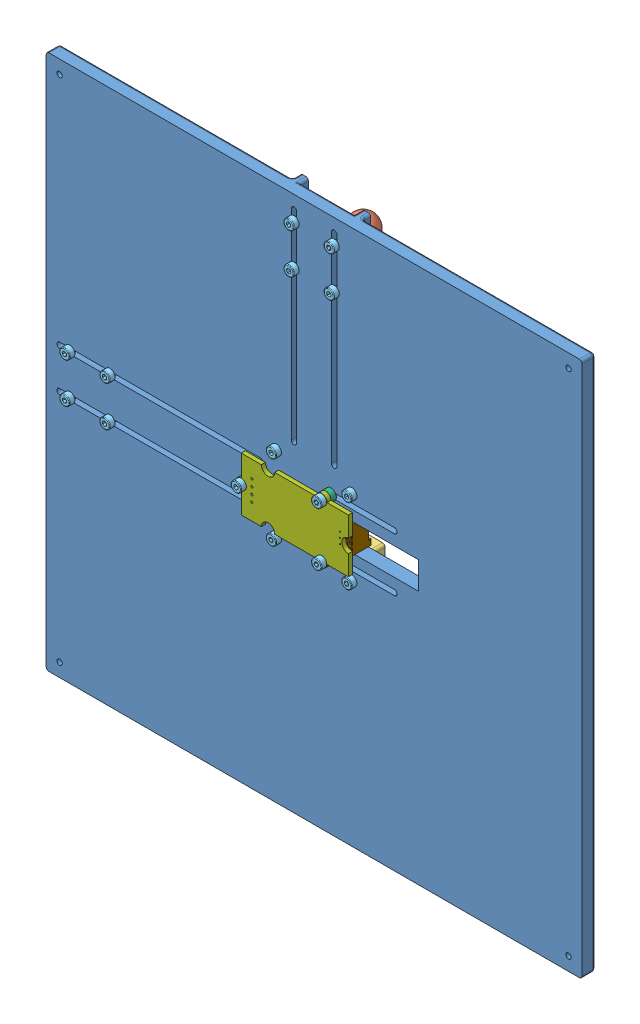
SolidWorks assembly plateau-complet, configuration Défaut. Lengths in mm.
Overall size (200 200 29.5).
45 component instances, 9 part files, 99 mates.
Components (placement in the parent):
- plateau-1: plateau [Défaut] at (22.8083 8.2939 197.5) size (200 200 8)
- support-sphere-ecrou_m2-4: support-sphere-ecrou_m2 [Défaut] at (-60.8917 8.2939 184.1699) x (0 -1 0) z (1 0 0) size (20 18.33 20)
- support-sphere-ecrou_m2-3: support-sphere-ecrou_m2 [Défaut] at (22.8083 91.9939 184.1699) x (1 0 0) z (0 1 0) size (20 18.33 20)
- support-fourchette-ecrou_m2-large-1: support-fourchette-ecrou_m2-large [Défaut] at (22.8083 8.2939 183.5) x (1 0 0) z (0 1 0) size (35 19 35)
- ecrou-h-6: ecrou-h [6007 HU M2] at (30.3083 99.4939 195.1) x (0.866025 -0.5 0) z (-0.5 -0.866025 0) size (4 1.6 4.62)
- ecrou-h-7: ecrou-h [6007 HU M2] at (15.3083 84.4939 195.1) x (-0.866025 -0.5 0) z (-0.5 0.866025 0) size (4 1.6 4.62)
- ecrou-h-8: ecrou-h [6007 HU M2] at (30.3083 84.4939 195.1) x (0.866025 0.5 0) z (0.5 -0.866025 0) size (4 1.6 4.62)
- ecrou-h-9: ecrou-h [6007 HU M2] at (15.3083 99.4939 195.1) x (0 -1 0) z (-1 0 0) size (4 1.6 4.62)
- ecrou-h-10: ecrou-h [6007 HU M2] at (-68.3917 15.7939 195.1) x (-0.5 -0.866025 0) z (-0.866025 0.5 0) size (4 1.6 4.62)
- ecrou-h-11: ecrou-h [6007 HU M2] at (-68.3917 0.7939 195.1) x (0.5 0.866025 0) z (0.866025 -0.5 0) size (4 1.6 4.62)
- ecrou-h-12: ecrou-h [6007 HU M2] at (-53.3917 0.7939 195.1) x (0.5 -0.866025 0) z (-0.866025 -0.5 0) size (4 1.6 4.62)
- ecrou-h-13: ecrou-h [6007 HU M2] at (-53.3917 15.7939 195.1) x (-0.5 -0.866025 0) z (-0.866025 0.5 0) size (4 1.6 4.62)
- vis-chc-15: vis-chc [Vis CHC M2x12] at (-53.3917 0.7939 202.5) x (0.832658 0.553787 0) z (0.553787 -0.832658 0) size (3.8 14 3.8)
- vis-chc-16: vis-chc [Vis CHC M2x12] at (-53.3917 15.7939 202.5) x (0.872712 0.488236 0) z (0.488236 -0.872712 0) size (3.8 14 3.8)
- vis-chc-17: vis-chc [Vis CHC M2x12] at (-68.3917 0.7939 202.5) x (0.878735 -0.477309 0) z (-0.477309 -0.878735 0) size (3.8 14 3.8)
- vis-chc-18: vis-chc [Vis CHC M2x12] at (-68.3917 15.7939 202.5) x (-0.020688 -0.999786 0) z (-0.999786 0.020688 0) size (3.8 14 3.8)
- vis-chc-19: vis-chc [Vis CHC M2x12] at (15.3083 84.4939 202.5) x (-0.459945 -0.887947 0) z (-0.887947 0.459945 0) size (3.8 14 3.8)
- vis-chc-20: vis-chc [Vis CHC M2x12] at (30.3083 84.4939 202.5) x (-0.307246 0.95163 0) z (0.95163 0.307246 0) size (3.8 14 3.8)
- vis-chc-21: vis-chc [Vis CHC M2x12] at (15.3083 99.4939 202.5) x (0.103271 -0.994653 0) z (-0.994653 -0.103271 0) size (3.8 14 3.8)
- vis-chc-22: vis-chc [Vis CHC M2x12] at (30.3083 99.4939 202.5) x (0.948564 0.316586 0) z (0.316586 -0.948564 0) size (3.8 14 3.8)
- vis-chc-23: vis-chc [Vis CHC M2x12] at (8.7083 22.3939 202.5) x (0.719096 0.694911 0) z (0.694911 -0.719096 0) size (3.8 14 3.8)
- vis-chc-24: vis-chc [Vis CHC M2x12] at (36.9083 22.3939 202.5) x (0.587191 0.809448 0) z (0.809448 -0.587191 0) size (3.8 14 3.8)
- vis-chc-25: vis-chc [Vis CHC M2x12] at (8.7083 -5.8061 202.5) x (0.239044 0.971009 0) z (0.971009 -0.239044 0) size (3.8 14 3.8)
- vis-chc-26: vis-chc [Vis CHC M2x12] at (36.9083 -5.8061 202.5) x (0.971464 0.237189 0) z (0.237189 -0.971464 0) size (3.8 14 3.8)
- ecrou-h-14: ecrou-h [6007 HU M2] at (8.7083 22.3939 195.16) x (0.866025 -0.5 0) z (-0.5 -0.866025 0) size (4 1.6 4.62)
- ecrou-h-15: ecrou-h [6007 HU M2] at (8.7083 -5.8061 195.16) x (0 -1 0) z (-1 0 0) size (4 1.6 4.62)
- ecrou-h-16: ecrou-h [6007 HU M2] at (36.9083 -5.8061 195.16) x (0.866025 -0.5 0) z (-0.5 -0.866025 0) size (4 1.6 4.62)
- ecrou-h-17: ecrou-h [6007 HU M2] at (36.9083 22.3939 195.16) x (0.866025 -0.5 0) z (-0.5 -0.866025 0) size (4 1.6 4.62)
- ecrou-h-18: ecrou-h [6007 HU M2] at (-72.1917 103.2939 200.5) x (0.866025 0.5 0) z (0.5 -0.866025 0) size (4 1.6 4.62)
- ecrou-h-19: ecrou-h [6007 HU M2] at (117.8083 103.2939 198.9) x (0.866025 0.5 0) z (-0.5 0.866025 0) size (4 1.6 4.62)
- ecrou-h-20: ecrou-h [6007 HU M2] at (-72.1917 -86.7061 200.5) x (0 -1 0) z (-1 0 0) size (4 1.6 4.62)
- ecrou-h-21: ecrou-h [6007 HU M2] at (117.8083 -86.7061 200.5) x (0 1 0) z (1 0 0) size (4 1.6 4.62)
- vis-chc-30: vis-chc [Vis CHC M2x8] at (29.1222 18.2939 206) x (-0.221467 -0.975168 0) z (-0.975168 0.221467 0) size (3.8 10 3.8)
- vis-chc-32: vis-chc [Vis CHC M2x8] at (29.1222 -1.7061 206) x (-0.923728 -0.383049 0) z (-0.383049 0.923728 0) size (3.8 10 3.8)
- vis-chc-33: vis-chc [Vis CHC M2x8] at (-0.8778 8.2939 206) x (-0.787107 -0.616816 0) z (-0.616816 0.787107 0) size (3.8 10 3.8)
- ecrou-h-24: ecrou-h [6007 HU M2] at (-0.8778 8.2939 197.9) x (0 -1 0) z (1 0 0) size (4 1.6 4.62)
- ecrou-h-25: ecrou-h [6007 HU M2] at (29.1222 -1.7061 197.9) x (0.866025 0.5 0) z (-0.5 0.866025 0) size (4 1.6 4.62)
- ecrou-h-26: ecrou-h [6007 HU M2] at (29.1222 18.2939 197.9) x (-0.866025 0.5 0) z (-0.5 -0.866025 0) size (4 1.6 4.62)
- entretoise-grove-1: entretoise-grove [Défaut] at (29.1222 18.2939 202.5) x (0.992185 0.124776 0) z (0 0 1) size (4 4 2)
- entretoise-grove-2: entretoise-grove [Défaut] at (-0.8778 8.2939 202.5) x (0.16979 0.98548 0) z (0 0 1) size (4 4 2)
- entretoise-grove-3: entretoise-grove [Défaut] at (29.1222 -1.7061 202.5) x (0.064788 0.997899 0) z (0 0 1) size (4 4 2)
- Grove IMU - droit-1: Grove IMU - droit [Défaut] at (21.1434 5.8987 163.25) x (0 -1 0) z (0 0 1) size (24 42 9.5)
  - Grove IMU Board-1: Grove IMU Board [Défaut] at (-2.3952 -22.0212 41.25) size (24 42 1.5)
  - MPU9150-1: MPU9150 [Défaut] at (-3.0078 -7.8003 40.45) size (4 4 0.8)
  - Connecteur Grove - droit-1: Connecteur Grove - droit [Défaut] at (-2.3952 11.9788 41.25) x (-1 0 0) z (0 -1 0) size (10 11 5)
Mates (geometry in assembly coordinates):
- Coïncidente5: coincident anti-aligned: plane of plateau-1 through (22.8083 8.2939 197.5) normal (0 0 -1); plane of support-sphere-ecrou_m2-4 through (-60.8917 8.2939 197.5) normal (0 0 1)
- Coïncidente8: coincident anti-aligned: plane of plateau-1 through (22.8083 8.2939 197.5) normal (0 0 -1); plane of support-sphere-ecrou_m2-3 through (22.8083 91.9939 197.5) normal (0 0 1)
- Coïncidente12: coincident anti-aligned: plane of plateau-1 through (22.8083 8.2939 197.5) normal (0 0 -1); plane of support-fourchette-ecrou_m2-large-1 through (22.8083 8.2939 197.5) normal (0 0 1)
- Coaxiale9: concentric anti-aligned: cylinder of support-sphere-ecrou_m2-3 through (30.3083 99.4939 197.501) axis (0 0 -1) radius 1; cylinder of ecrou-h-m2-6 through (30.3083 99.4939 193.5) axis (0 0 1) radius 0.7835
- Coïncidente26: coincident anti-aligned: plane of support-sphere-ecrou_m2-3 through (22.8083 91.9939 195.1) normal (0 0 -1); plane of ecrou-h-m2-6 through (32.6177 99.4939 195.1) normal (0 0 1)
- Parallèle1: parallel anti-aligned: plane of support-sphere-ecrou_m2-3 through (27.9783 99.4939 195.1) normal (0.866025 -0.5 0); plane of ecrou-h-m2-6 through (29.1536 101.4939 193.5) normal (-0.866025 0.5 0)
- Coaxiale10: concentric anti-aligned: cylinder of support-sphere-ecrou_m2-3 through (15.3083 99.4939 197.501) axis (0 0 -1) radius 1; cylinder of ecrou-h-m2-9 through (15.3083 99.4939 193.5) axis (0 0 1) radius 0.7835
- Parallèle2: parallel anti-aligned: plane of support-sphere-ecrou_m2-3 through (14.1433 101.5118 195.1) normal (0 -1 0); plane of ecrou-h-m2-9 through (16.463 101.4939 193.5) normal (0 1 0)
- Coïncidente29: coincident anti-aligned: plane of support-sphere-ecrou_m2-3 through (22.8083 91.9939 195.1) normal (0 0 -1); plane of ecrou-h-m2-9 through (16.463 97.4939 195.1) normal (0 0 1)
- Coaxiale11: concentric anti-aligned: cylinder of support-sphere-ecrou_m2-3 through (15.3083 84.4939 197.501) axis (0 0 -1) radius 1; cylinder of ecrou-h-m2-7 through (15.3083 84.4939 193.5) axis (0 0 1) radius 0.7835
- Parallèle3: parallel anti-aligned: plane of support-sphere-ecrou_m2-3 through (12.9783 84.4939 195.1) normal (0.866025 -0.5 0); plane of ecrou-h-m2-7 through (14.1536 86.4939 193.5) normal (-0.866025 0.5 0)
- Coïncidente31: coincident anti-aligned: plane of support-sphere-ecrou_m2-3 through (22.8083 91.9939 195.1) normal (0 0 -1); plane of ecrou-h-m2-7 through (14.1536 82.4939 195.1) normal (0 0 1)
- Coaxiale12: concentric anti-aligned: cylinder of support-sphere-ecrou_m2-3 through (30.3083 84.4939 197.501) axis (0 0 -1) radius 1; cylinder of ecrou-h-m2-8 through (30.3083 84.4939 193.5) axis (0 0 1) radius 0.7835
- Parallèle4: parallel anti-aligned: plane of support-sphere-ecrou_m2-3 through (32.6383 84.4939 195.1) normal (-0.866025 0.5 0); plane of ecrou-h-m2-8 through (31.463 82.4939 193.5) normal (0.866025 -0.5 0)
- Coïncidente32: coincident anti-aligned: plane of support-sphere-ecrou_m2-3 through (22.8083 91.9939 195.1) normal (0 0 -1); plane of ecrou-h-m2-8 through (31.463 86.4939 195.1) normal (0 0 1)
- Coaxiale13: concentric anti-aligned: cylinder of support-sphere-ecrou_m2-4 through (-68.3917 15.7939 197.501) axis (0 0 -1) radius 1; cylinder of ecrou-h-m2-10 through (-68.3917 15.7939 193.5) axis (0 0 1) radius 0.7835
- Coaxiale14: concentric anti-aligned: cylinder of support-sphere-ecrou_m2-4 through (-68.3917 0.7939 197.501) axis (0 0 -1) radius 1; cylinder of ecrou-h-m2-11 through (-68.3917 0.7939 193.5) axis (0 0 1) radius 0.7835
- Coaxiale15: concentric anti-aligned: cylinder of support-sphere-ecrou_m2-4 through (-53.3917 0.7939 197.501) axis (0 0 -1) radius 1; cylinder of ecrou-h-m2-12 through (-53.3917 0.7939 193.5) axis (0 0 1) radius 0.7835
- Coaxiale16: concentric anti-aligned: cylinder of support-sphere-ecrou_m2-4 through (-53.3917 15.7939 197.501) axis (0 0 -1) radius 1; cylinder of ecrou-h-m2-13 through (-53.3917 15.7939 193.5) axis (0 0 1) radius 0.7835
- Parallèle5: parallel anti-aligned: plane of support-sphere-ecrou_m2-4 through (-51.3738 16.9589 195.1) normal (-1 0 0); plane of ecrou-h-m2-13 through (-51.3917 14.6392 193.5) normal (1 0 0)
- Parallèle6: parallel anti-aligned: plane of support-sphere-ecrou_m2-4 through (-66.3738 16.9589 195.1) normal (-1 0 0); plane of ecrou-h-m2-10 through (-66.3917 14.6392 193.5) normal (1 0 0)
- Parallèle7: parallel anti-aligned: plane of support-sphere-ecrou_m2-4 through (-66.3738 -0.3711 195.1) normal (-0.5 0.866025 0); plane of ecrou-h-m2-11 through (-68.3917 -1.5155 193.5) normal (0.5 -0.866025 0)
- Parallèle8: parallel anti-aligned: plane of support-sphere-ecrou_m2-4 through (-51.3738 -0.3711 195.1) normal (-0.5 0.866025 0); plane of ecrou-h-m2-12 through (-53.3917 -1.5155 193.5) normal (0.5 -0.866025 0)
- Coïncidente37: coincident anti-aligned: plane of support-sphere-ecrou_m2-4 through (-60.8917 8.2939 195.1) normal (0 0 -1); plane of ecrou-h-m2-10 through (-68.3917 13.4845 195.1) normal (0 0 1)
- Coïncidente38: coincident anti-aligned: plane of support-sphere-ecrou_m2-4 through (-60.8917 8.2939 195.1) normal (0 0 -1); plane of ecrou-h-m2-13 through (-53.3917 13.4845 195.1) normal (0 0 1)
- Coïncidente39: coincident anti-aligned: plane of support-sphere-ecrou_m2-4 through (-60.8917 8.2939 195.1) normal (0 0 -1); plane of ecrou-h-m2-11 through (-68.3917 3.1033 195.1) normal (0 0 1)
- Coïncidente40: coincident anti-aligned: plane of support-sphere-ecrou_m2-4 through (-60.8917 8.2939 195.1) normal (0 0 -1); plane of ecrou-h-m2-12 through (-51.3917 -0.3608 195.1) normal (0 0 1)
- Coaxiale17: concentric anti-aligned: cylinder of support-sphere-ecrou_m2-3 through (30.3083 99.4939 197.501) axis (0 0 -1) radius 1; cylinder of vis-chc-m2x10-8 through (30.3083 99.4939 190.5) axis (0 0 1) radius 1
- Coaxiale18: concentric anti-aligned: cylinder of support-sphere-ecrou_m2-3 through (15.3083 99.4939 197.501) axis (0 0 -1) radius 1; cylinder of vis-chc-m2x10-9 through (15.3083 99.4939 190.5) axis (0 0 1) radius 1
- Coaxiale19: concentric anti-aligned: cylinder of support-sphere-ecrou_m2-3 through (30.3083 84.4939 197.501) axis (0 0 -1) radius 1; cylinder of vis-chc-m2x10-11 through (30.3083 84.4939 190.5) axis (0 0 1) radius 1
- Coaxiale20: concentric anti-aligned: cylinder of support-sphere-ecrou_m2-3 through (15.3083 84.4939 197.501) axis (0 0 -1) radius 1; cylinder of vis-chc-m2x10-10 through (15.3083 84.4939 190.5) axis (0 0 1) radius 1
- Coaxiale21: concentric anti-aligned: cylinder of support-sphere-ecrou_m2-4 through (-53.3917 0.7939 197.501) axis (0 0 -1) radius 1; cylinder of vis-chc-m2-15 through (-53.3917 0.7939 190.5) axis (0 0 1) radius 1
- Coaxiale22: concentric anti-aligned: cylinder of support-sphere-ecrou_m2-4 through (-68.3917 0.7939 197.501) axis (0 0 -1) radius 1; cylinder of vis-chc-m2-17 through (-68.3917 0.7939 190.5) axis (0 0 1) radius 1
- Coaxiale23: concentric anti-aligned: cylinder of support-sphere-ecrou_m2-4 through (-68.3917 15.7939 197.501) axis (0 0 -1) radius 1; cylinder of vis-chc-m2-18 through (-68.3917 15.7939 190.5) axis (0 0 1) radius 1
- Coaxiale24: concentric anti-aligned: cylinder of support-sphere-ecrou_m2-4 through (-53.3917 15.7939 197.501) axis (0 0 -1) radius 1; cylinder of vis-chc-m2-16 through (-53.3917 15.7939 190.5) axis (0 0 1) radius 1
- Coïncidente41: coincident anti-aligned: plane of plateau-1 through (22.8083 8.2939 202.5) normal (0 0 1); plane of vis-chc-m2x10-10 through (15.3083 84.4939 202.5) normal (0 0 -1)
- Coïncidente42: coincident anti-aligned: plane of plateau-1 through (22.8083 8.2939 202.5) normal (0 0 1); plane of vis-chc-m2x10-9 through (15.3083 99.4939 202.5) normal (0 0 -1)
- Coïncidente43: coincident anti-aligned: plane of plateau-1 through (22.8083 8.2939 202.5) normal (0 0 1); plane of vis-chc-m2x10-8 through (30.3083 99.4939 202.5) normal (0 0 -1)
- Coïncidente44: coincident anti-aligned: plane of plateau-1 through (22.8083 8.2939 202.5) normal (0 0 1); plane of vis-chc-m2x10-11 through (30.3083 84.4939 202.5) normal (0 0 -1)
- Coïncidente45: coincident anti-aligned: plane of plateau-1 through (22.8083 8.2939 202.5) normal (0 0 1); plane of vis-chc-m2-17 through (-68.3917 0.7939 202.5) normal (0 0 -1)
- Coïncidente46: coincident anti-aligned: plane of plateau-1 through (22.8083 8.2939 202.5) normal (0 0 1); plane of vis-chc-m2-15 through (-53.3917 0.7939 202.5) normal (0 0 -1)
- Coïncidente47: coincident anti-aligned: plane of plateau-1 through (22.8083 8.2939 202.5) normal (0 0 1); plane of vis-chc-m2-16 through (-53.3917 15.7939 202.5) normal (0 0 -1)
- Coïncidente48: coincident anti-aligned: plane of plateau-1 through (22.8083 8.2939 202.5) normal (0 0 1); plane of vis-chc-m2-18 through (-68.3917 15.7939 202.5) normal (0 0 -1)
- Distance6: distance = 13.8 mm: cylinder of support-sphere-ecrou_m2-4 through (-60.8917 8.2939 193.5) axis (0 0 1) radius 2.5; plane of plateau-1 through (-77.1917 108.2939 202.5) normal (-1 0 0)
- Distance7: distance = 13.8 mm: cylinder of support-sphere-ecrou_m2-3 through (22.8083 91.9939 193.5) axis (0 0 1) radius 2.5; plane of plateau-1 through (-77.1917 108.2939 202.5) normal (0 1 0)
- Coaxiale25: concentric anti-aligned: cylinder of support-fourchette-ecrou_m2-large-1 through (36.9083 22.3939 197.501) axis (0 0 -1) radius 1; cylinder of ecrou-h-m2-17 through (36.9083 22.3939 193.56) axis (0 0 1) radius 0.7835
- Parallèle9: parallel anti-aligned: plane of support-fourchette-ecrou_m2-large-1 through (35.7433 24.4118 195.16) normal (0 -1 0); plane of ecrou-h-m2-17 through (38.063 24.3939 193.56) normal (0 1 0)
- Coïncidente50: coincident anti-aligned: plane of support-fourchette-ecrou_m2-large-1 through (22.8083 8.2939 195.16) normal (0 0 -1); plane of ecrou-h-m2-17 through (39.2177 22.3939 195.16) normal (0 0 1)
- Coaxiale26: concentric anti-aligned: cylinder of support-fourchette-ecrou_m2-large-1 through (36.9083 -5.8061 197.501) axis (0 0 -1) radius 1; cylinder of ecrou-h-m2-16 through (36.9083 -5.8061 193.56) axis (0 0 1) radius 0.7835
- Coïncidente51: coincident anti-aligned: plane of support-fourchette-ecrou_m2-large-1 through (22.8083 8.2939 195.16) normal (0 0 -1); plane of ecrou-h-m2-16 through (39.2177 -5.8061 195.16) normal (0 0 1)
- Parallèle10: parallel anti-aligned: plane of support-fourchette-ecrou_m2-large-1 through (35.7433 -3.7882 195.16) normal (0 -1 0); plane of ecrou-h-m2-16 through (38.063 -3.8061 193.56) normal (0 1 0)
- Coaxiale27: concentric anti-aligned: cylinder of support-fourchette-ecrou_m2-large-1 through (8.7083 -5.8061 197.501) axis (0 0 -1) radius 1; cylinder of ecrou-h-m2-15 through (8.7083 -5.8061 193.56) axis (0 0 1) radius 0.7835
- Parallèle11: parallel anti-aligned: plane of support-fourchette-ecrou_m2-large-1 through (9.8733 -7.8239 195.16) normal (0 1 0); plane of ecrou-h-m2-15 through (7.5536 -7.8061 193.56) normal (0 -1 0)
- Coïncidente54: coincident anti-aligned: plane of support-fourchette-ecrou_m2-large-1 through (22.8083 8.2939 195.16) normal (0 0 -1); plane of ecrou-h-m2-15 through (9.863 -7.8061 195.16) normal (0 0 1)
- Coaxiale28: concentric anti-aligned: cylinder of support-fourchette-ecrou_m2-large-1 through (8.7083 22.3939 197.501) axis (0 0 -1) radius 1; cylinder of ecrou-h-m2-14 through (8.7083 22.3939 193.56) axis (0 0 1) radius 0.7835
- Parallèle12: parallel anti-aligned: plane of support-fourchette-ecrou_m2-large-1 through (7.5433 24.4118 195.16) normal (0 -1 0); plane of ecrou-h-m2-14 through (9.863 24.3939 193.56) normal (0 1 0)
- Coïncidente56: coincident anti-aligned: plane of support-fourchette-ecrou_m2-large-1 through (22.8083 8.2939 195.16) normal (0 0 -1); plane of ecrou-h-m2-14 through (11.0177 22.3939 195.16) normal (0 0 1)
- Coaxiale29: concentric anti-aligned: cylinder of plateau-1 through (8.7083 -5.8061 202.501) axis (0 0 -1) radius 1; cylinder of vis-chc-m2-25 through (8.7083 -5.8061 190.5) axis (0 0 1) radius 1
- Coïncidente57: coincident anti-aligned: plane of plateau-1 through (22.8083 8.2939 202.5) normal (0 0 1); plane of vis-chc-m2-25 through (8.7083 -5.8061 202.5) normal (0 0 -1)
- Coaxiale30: concentric anti-aligned: cylinder of plateau-1 through (36.9083 -5.8061 202.501) axis (0 0 -1) radius 1; cylinder of vis-chc-26 through (36.9083 -5.8061 190.5) axis (0 0 1) radius 1
- Coïncidente58: coincident anti-aligned: plane of plateau-1 through (22.8083 8.2939 202.5) normal (0 0 1); plane of vis-chc-26 through (36.9083 -5.8061 202.5) normal (0 0 -1)
- Coaxiale31: concentric anti-aligned: cylinder of plateau-1 through (8.7083 22.3939 202.501) axis (0 0 -1) radius 1; cylinder of vis-chc-m2-23 through (8.7083 22.3939 190.5) axis (0 0 1) radius 1
- Coïncidente59: coincident anti-aligned: plane of plateau-1 through (22.8083 8.2939 202.5) normal (0 0 1); plane of vis-chc-m2-23 through (8.7083 22.3939 202.5) normal (0 0 -1)
- Coaxiale32: concentric anti-aligned: cylinder of plateau-1 through (36.9083 22.3939 202.501) axis (0 0 -1) radius 1; cylinder of vis-chc-m2-24 through (36.9083 22.3939 190.5) axis (0 0 1) radius 1
- Coïncidente60: coincident anti-aligned: plane of plateau-1 through (22.8083 8.2939 202.5) normal (0 0 1); plane of vis-chc-m2-24 through (36.9083 22.3939 202.5) normal (0 0 -1)
- Coaxiale33: concentric anti-aligned: circle of plateau-1; circle of ecrou-h-m2-19
- Coaxiale34: concentric anti-aligned: cylinder of plateau-1 through (-72.1917 103.2939 202.501) axis (0 0 -1) radius 1; cylinder of ecrou-h-m2-18 through (-72.1917 103.2939 198.9) axis (0 0 1) radius 0.7835
- Coaxiale35: concentric anti-aligned: cylinder of plateau-1 through (-72.1917 -86.7061 202.501) axis (0 0 -1) radius 1; cylinder of ecrou-h-m2-20 through (-72.1917 -86.7061 198.9) axis (0 0 1) radius 0.7835
- Coaxiale36: concentric anti-aligned: cylinder of plateau-1 through (117.8083 -86.7061 202.501) axis (0 0 -1) radius 1; cylinder of ecrou-h-m2-21 through (117.8083 -86.7061 198.9) axis (0 0 1) radius 0.7835
- Coaxiale37: concentric aligned: cylinder of ecrou-h-m2-16 through (36.9083 -5.8061 193.56) axis (0 0 1) radius 0.7835; cylinder of vis-chc-26 through (36.9083 -5.8061 190.5) axis (0 0 1) radius 1
- Coaxiale38: concentric aligned: cylinder of ecrou-h-m2-14 through (8.7083 22.3939 193.56) axis (0 0 1) radius 0.7835; cylinder of vis-chc-m2-23 through (8.7083 22.3939 190.5) axis (0 0 1) radius 1
- Parallèle13: parallel aligned: plane of plateau-1 through (-77.1917 108.2939 202.5) normal (0 1 0); plane of support-sphere-ecrou_m2-3 through (12.8083 101.9939 197.5) normal (0 1 0)
- Distance8: distance = 0.1 mm anti-aligned: plane of support-sphere-ecrou_m2-3 through (12.8083 101.9939 197.5) normal (-1 0 0); plane of plateau-1 through (12.7083 28.2939 194.5) normal (1 0 0)
- Parallèle14: parallel aligned: plane of plateau-1 through (-77.1917 108.2939 202.5) normal (-1 0 0); plane of support-sphere-ecrou_m2-4 through (-70.8917 18.2939 197.5) normal (-1 0 0)
- Distance9: distance = 0.1 mm anti-aligned: plane of support-sphere-ecrou_m2-4 through (-50.8917 18.2939 197.5) normal (0 1 0); plane of plateau-1 through (2.8083 18.3939 194.5) normal (0 -1 0)
- Parallèle15: parallel aligned: plane of plateau-1 through (122.8083 108.2939 202.5) normal (1 0 0); plane of Grove IMU - droit-1/Grove IMU Board-1 through (39.1222 -1.7061 206) normal (1 0 0)
- Tangent1: tangent anti-aligned: plane of plateau-1 through (27.8083 -2.7061 194.499) normal (0 1 0); cylinder of Grove IMU - droit-1/Grove IMU Board-1 through (29.1222 -1.7061 204.5) axis (0 0 1) radius 1
- Distance10: distance = 2 mm anti-aligned: plane of Grove IMU - droit-1/Grove IMU Board-1 through (9.1222 18.2939 204.5) normal (0 0 -1); plane of plateau-1 through (22.8083 8.2939 202.5) normal (0 0 1)
- Coaxiale45: concentric aligned: cylinder of Grove IMU - droit-1/Grove IMU Board-1 through (29.1222 18.2939 204.5) axis (0 0 1) radius 1; cylinder of vis-chc-30 through (29.1222 18.2939 198) axis (0 0 1) radius 1
- Coïncidente70: coincident anti-aligned: plane of Grove IMU - droit-1/Grove IMU Board-1 through (9.1222 18.2939 206) normal (0 0 1); plane of vis-chc-30 through (29.1222 18.2939 206) normal (0 0 -1)
- Coaxiale46: concentric anti-aligned: cylinder of vis-chc-30 through (29.1222 18.2939 198) axis (0 0 1) radius 1; cylinder of ecrou-h-26 through (29.1222 18.2939 199.5) axis (0 0 -1) radius 0.7835
- Parallèle18: parallel anti-aligned: plane of plateau-1 through (55.8083 20.3939 199.5) normal (0 -1 0); plane of ecrou-h-26 through (27.9675 20.2939 199.5) normal (0 1 0)
- Coïncidente72: coincident anti-aligned: plane of plateau-1 through (22.8083 8.2939 199.5) normal (0 0 -1); plane of ecrou-h-26 through (27.9675 20.2939 199.5) normal (0 0 1)
- Coaxiale47: concentric aligned: cylinder of Grove IMU - droit-1/Grove IMU Board-1 through (29.1222 -1.7061 204.5) axis (0 0 1) radius 1; cylinder of vis-chc-32 through (29.1222 -1.7061 198) axis (0 0 1) radius 1
- Coaxiale48: concentric aligned: cylinder of Grove IMU - droit-1/Grove IMU Board-1 through (-0.8778 8.2939 204.5) axis (0 0 1) radius 1; cylinder of vis-chc-33 through (-0.8778 8.2939 198) axis (0 0 1) radius 1
- Coïncidente73: coincident anti-aligned: plane of Grove IMU - droit-1/Grove IMU Board-1 through (9.1222 18.2939 206) normal (0 0 1); plane of vis-chc-32 through (29.1222 -1.7061 206) normal (0 0 -1)
- Coïncidente74: coincident anti-aligned: plane of Grove IMU - droit-1/Grove IMU Board-1 through (9.1222 18.2939 206) normal (0 0 1); plane of vis-chc-33 through (-0.8778 8.2939 206) normal (0 0 -1)
- Coaxiale50: concentric anti-aligned: cylinder of vis-chc-32 through (29.1222 -1.7061 198) axis (0 0 1) radius 1; cylinder of ecrou-h-25 through (29.1222 -1.7061 199.5) axis (0 0 -1) radius 0.7835
- Parallèle19: parallel anti-aligned: plane of plateau-1 through (55.8083 0.3939 199.5) normal (0 -1 0); plane of ecrou-h-25 through (27.9675 0.2939 199.5) normal (0 1 0)
- Coïncidente76: coincident anti-aligned: plane of plateau-1 through (22.8083 8.2939 199.5) normal (0 0 -1); plane of ecrou-h-25 through (31.4316 -1.7061 199.5) normal (0 0 1)
- Coaxiale51: concentric anti-aligned: cylinder of vis-chc-33 through (-0.8778 8.2939 198) axis (0 0 1) radius 1; cylinder of ecrou-h-24 through (-0.8778 8.2939 199.5) axis (0 0 -1) radius 0.7835
- Parallèle20: parallel anti-aligned: plane of plateau-1 through (25.8083 10.3939 199.5) normal (0 -1 0); plane of ecrou-h-24 through (-2.0325 10.2939 199.5) normal (0 1 0)
- Coïncidente78: coincident anti-aligned: plane of plateau-1 through (22.8083 8.2939 199.5) normal (0 0 -1); plane of ecrou-h-24 through (-2.0325 6.2939 199.5) normal (0 0 1)
- Coaxiale52: concentric anti-aligned: cylinder of vis-chc-32 through (29.1222 -1.7061 198) axis (0 0 1) radius 1; cylinder of entretoise-grove-3 through (29.1222 -1.7061 204.5) axis (0 0 -1) radius 1
- Coïncidente79: coincident anti-aligned: plane of plateau-1 through (22.8083 8.2939 202.5) normal (0 0 1); plane of entretoise-grove-3 through (29.1222 -1.7061 202.5) normal (0 0 -1)
- Coaxiale53: concentric anti-aligned: cylinder of vis-chc-30 through (29.1222 18.2939 198) axis (0 0 1) radius 1; cylinder of entretoise-grove-1 through (29.1222 18.2939 204.5) axis (0 0 -1) radius 1
- Coïncidente80: coincident anti-aligned: plane of plateau-1 through (22.8083 8.2939 202.5) normal (0 0 1); plane of entretoise-grove-1 through (29.1222 18.2939 202.5) normal (0 0 -1)
- Coaxiale54: concentric anti-aligned: cylinder of vis-chc-33 through (-0.8778 8.2939 198) axis (0 0 1) radius 1; cylinder of entretoise-grove-2 through (-0.8778 8.2939 204.5) axis (0 0 -1) radius 1
- Coïncidente81: coincident anti-aligned: plane of plateau-1 through (22.8083 8.2939 202.5) normal (0 0 1); plane of entretoise-grove-2 through (-0.8778 8.2939 202.5) normal (0 0 -1)
